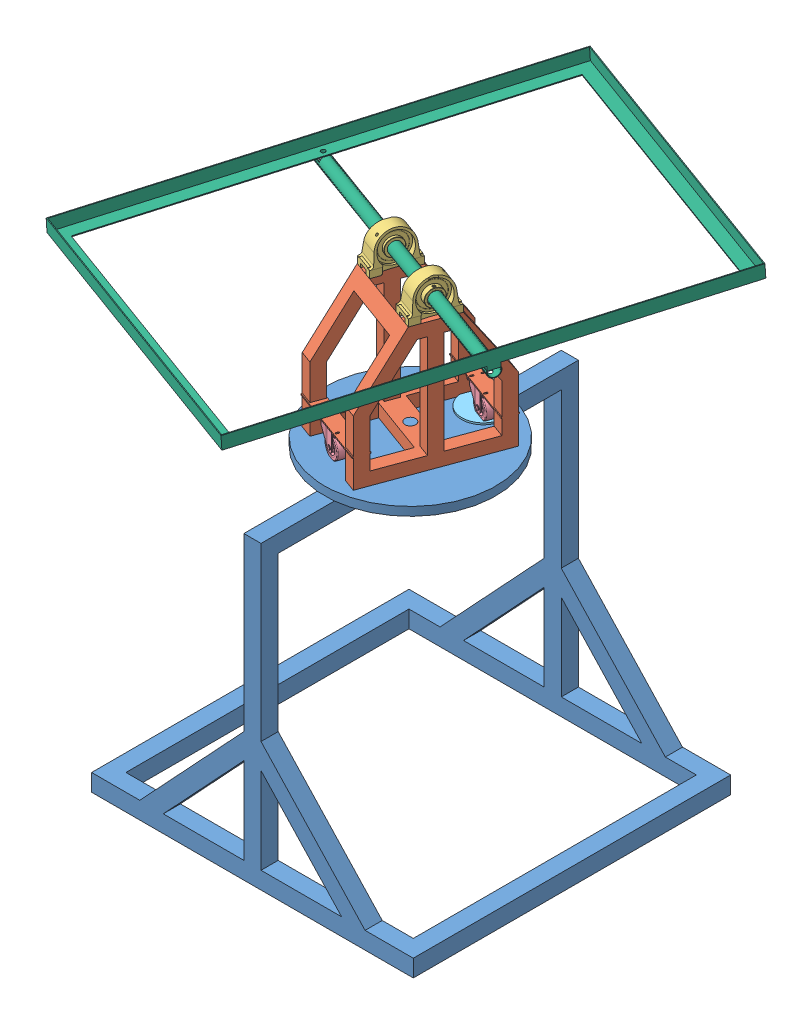
SolidWorks assembly akhir, configuration Default. Lengths in mm.
Overall size (1200.51 1137.94 1368.68).
8 component instances, 6 part files, 16 mates.
Components (placement in the parent):
- bawah-1: bawah [Default] at (129.039 286.6255 799.0519) size (750 800 740)
- atas-1: atas [Default] at (-32.0633 626.1544 1150.4926) x (0.343929 0 -0.938996) z (0.938996 0 0.343929) size (304.09 300 300)
- bearing-1: bearing [Default] at (-3.728 823.0354 1142.9133) x (-0.938996 0 -0.343929) z (0.343929 0 -0.938996) size (48 114.17 100.92)
- roda-2: roda [Valor predeterminado] at (21.2053 545.1354 1295.8163) x (0.938996 0 0.343929) z (-0.343929 0 0.938996) size (89.51 68.01 60.03)
- roda-3: roda [Valor predeterminado] at (114.0661 545.1354 1042.2875) x (0.938996 0 0.343929) z (-0.343929 0 0.938996) size (89.51 68.01 60.03)
- bearing-3: bearing [Default] at (138.9994 823.0354 1195.1905) x (0.938996 0 0.343929) z (-0.343929 0 0.938996) size (48 114.17 100.92)
- putaran-3: putaran [Default] at (98.4526 480.1354 1030.8312) x (0.766112 0 -0.642707) z (0.642707 0 0.766112) size (100 4 100)
- as-3: as [Default] at (-294.0469 796.4745 932.4205) x (0.343432 0.053743 -0.937639) z (0.938996 0 0.343929) size (990 79.2 685)
Mates (geometry in assembly coordinates):
- Coincident2: coincident aligned: line of atas-1 through (-9.0674 780.1354 1087.7092) axis (-0.343929 0 0.938996); line of bearing-1 through (-9.0674 780.1354 1087.7092) axis (-0.343929 0 0.938996)
- Coincident3: coincident aligned: line of atas-1 through (19.1025 780.1354 1098.0271) axis (-0.938996 0 -0.343929); line of bearing-1 through (3.4917 780.1354 1092.3093) axis (-0.938996 0 -0.343929)
- Coincident10: coincident anti-aligned: plane of atas-1 through (-32.0633 545.1354 1150.4926) normal (0 -1 0); plane of roda-2 through (-10.1991 545.1354 1298.6908) normal (0 1 0)
- Concentric4: concentric anti-aligned: circle of atas-1; circle of roda-2
- Concentric5: concentric anti-aligned: circle of atas-1; circle of roda-2
- Coincident11: coincident anti-aligned: plane of atas-1 through (-32.0633 545.1354 1150.4926) normal (0 -1 0); plane of roda-3 through (82.6617 545.1354 1045.162) normal (0 1 0)
- Concentric6: concentric anti-aligned: circle of atas-1; circle of roda-3
- Concentric7: concentric aligned: circle of atas-1; circle of roda-3
- Coincident12: coincident anti-aligned: plane of atas-1 through (155.7359 780.1354 1219.2784) normal (0 1 0); plane of bearing-3 through (133.1611 780.1354 1280.9119) normal (0 -1 0)
- Coincident13: coincident anti-aligned: line of atas-1 through (178.7317 780.1354 1156.495) axis (-0.343929 0 0.938996); line of bearing-3 through (171.3373 780.1354 1176.6834) axis (0.343929 0 -0.938996)
- Coincident14: coincident anti-aligned: line of atas-1 through (178.7317 780.1354 1156.495) axis (-0.938996 0 -0.343929); line of bearing-3 through (166.1727 780.1354 1151.895) axis (0.938996 0 0.343929)
- Coincident15: coincident anti-aligned: plane of bawah-1 through (67.6357 480.1354 1169.0519) normal (0 1 0); plane of atas-1 through (155.7359 480.1354 1219.2784) normal (0 -1 0)
- Concentric8: concentric aligned: cylinder of bawah-1 through (67.6357 510.1354 1169.0519) axis (0 -1 0) radius 12.5; cylinder of atas-1 through (67.6357 673.1354 1169.0519) axis (0 -1 0) radius 12.5
- Coincident18: coincident anti-aligned: plane of bawah-1 through (67.6357 480.1354 1169.0519) normal (0 1 0); plane of putaran-3 through (93.8798 480.1354 1025.2132) normal (0 -1 0)
- Tangent2: tangent anti-aligned: cylinder of bawah-1 through (69.1623 500.1354 995.7498) axis (0 -1 0) radius 5; plane of putaran-3 through (91.2832 484.1354 1014.3386) normal (-0.766112 0 0.642707)
- Concentric12: concentric aligned: cylinder of bearing-3 through (159.7512 823.0354 1202.7913) axis (-0.938996 0 -0.343929) radius 12.5; cylinder of as-3 through (423.5124 823.0354 1299.4) axis (-0.938996 0 -0.343929) radius 14
